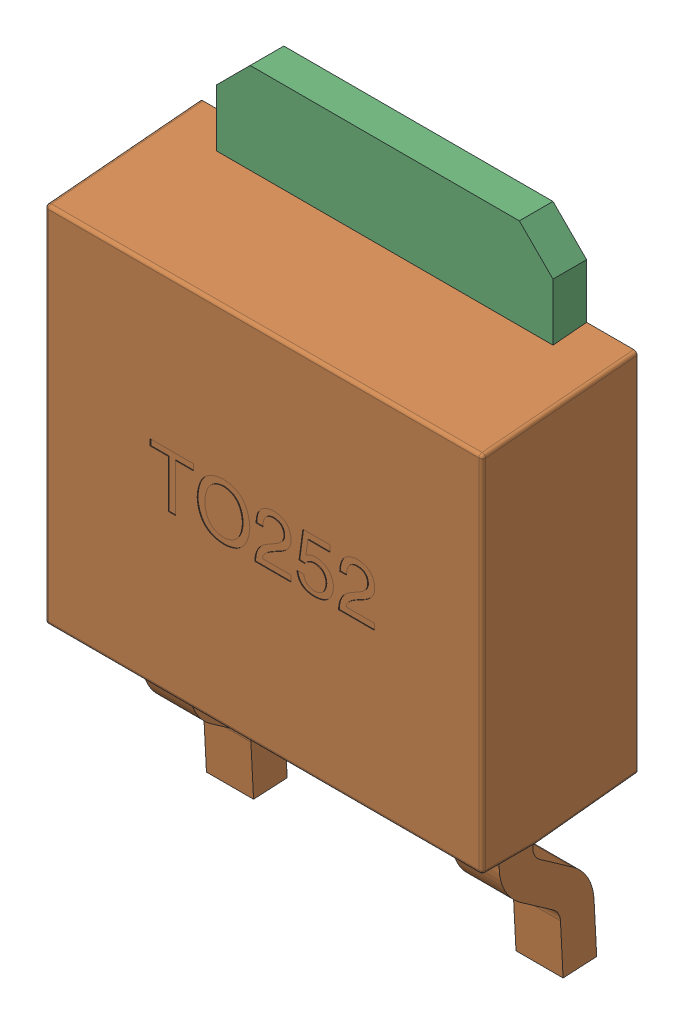
SolidWorks assembly MTG1, configuration 默认. Lengths in mm.
Overall size (6.5 9.42 2.31).
3 component instances, 2 part files, 0 mates.
Components (placement in the parent):
- TO252-1: TO252 [默认] at (74.916 61.9891 0) size (6.5 9.42 2.31)
  - LOGO_-1: LOGO_ [默认] at (2.3503 3.4211 -0.0025) x (-1 0 0) z (0 0 -1) size (0.75 0.87 0.01)
  - TO252-1: TO252 [默认] at origin size (6.5 9.42 2.3)
